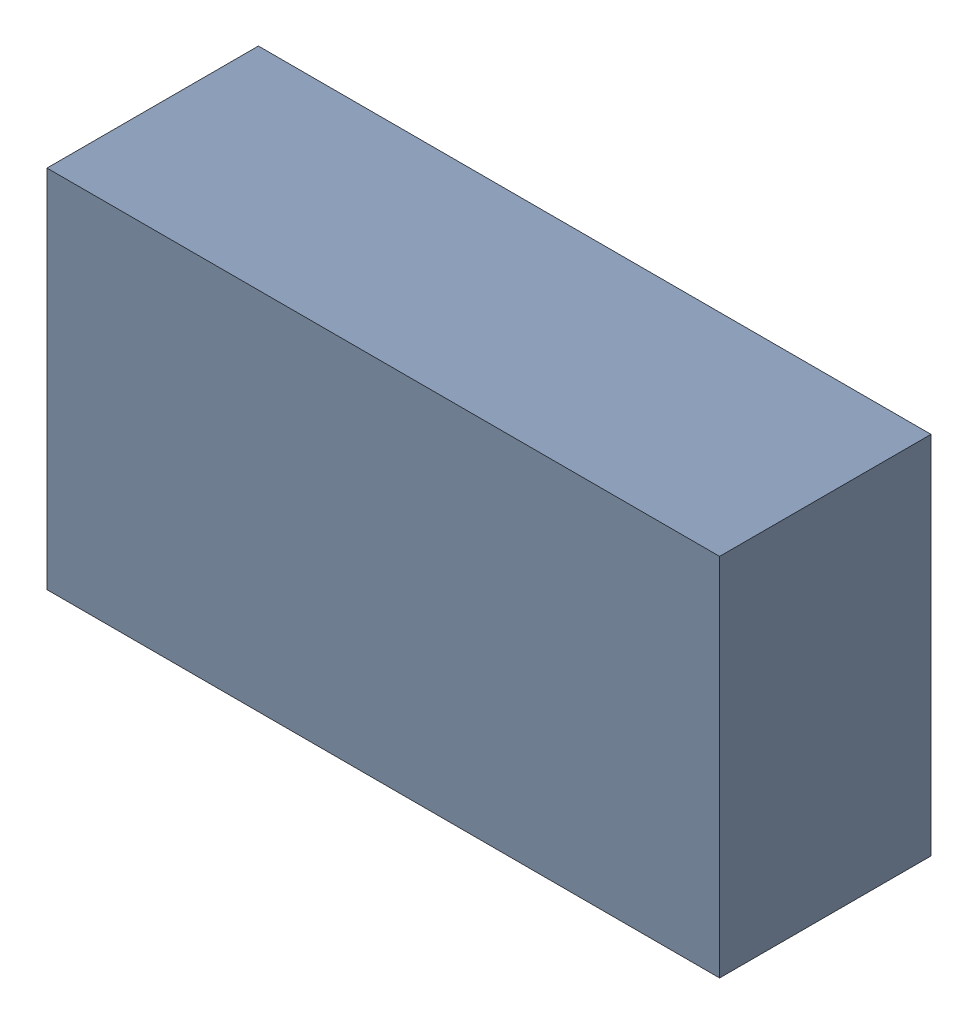
SolidWorks assembly L1_TDA4, configuration Standard. Lengths in mm.
Overall size (1.75 0.95 0.55).
2 component instances, 1 part files, 0 mates.
Components (placement in the parent):
- 885542648-1: 885542648 [Standard] at (-0.82 -56.09 0) size (1.75 0.95 0.55)
  - Extruded_19-1: Extruded_19 [Standard] at origin size (1.75 0.95 0.55)
